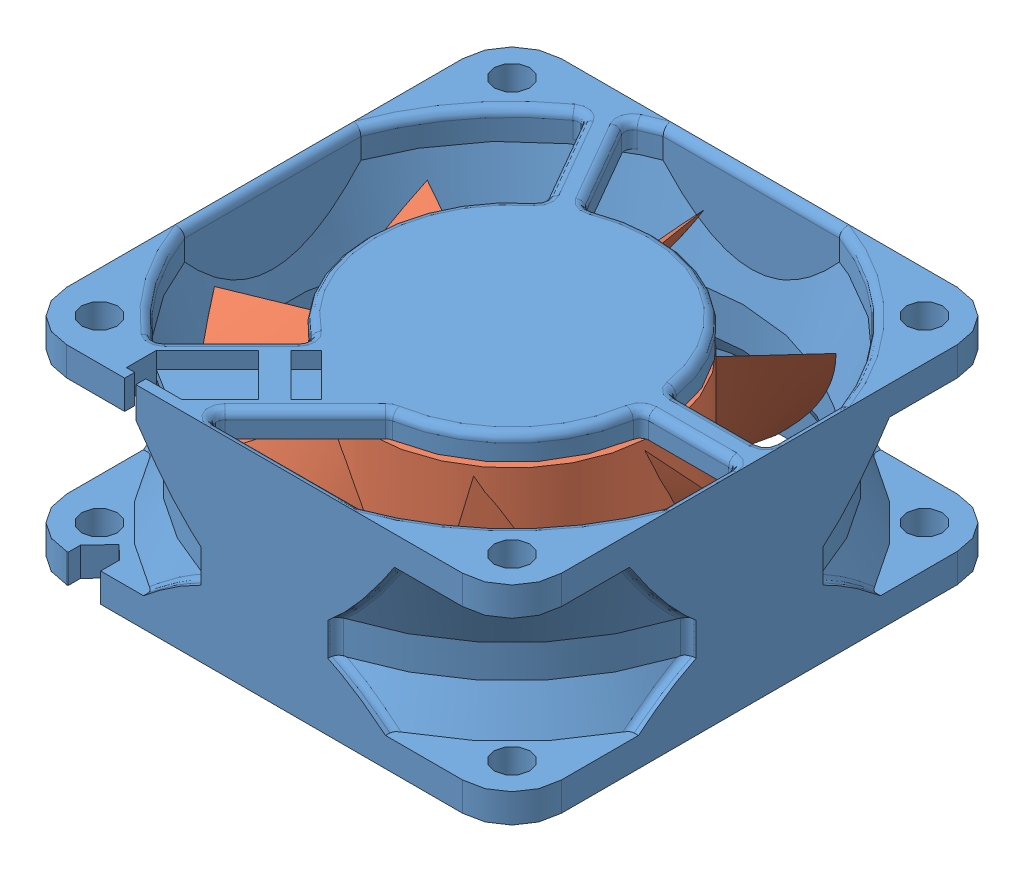
SolidWorks assembly Ventola_50x50, configuration Default. Lengths in mm.
Overall size (60.11 25.2 60.11).
2 component instances, 2 part files, 6 mates.
Components (placement in the parent):
- ventola_1-1: ventola_1 [Default] at origin size (60.11 25.2 60.11)
- ventola_2-1: ventola_2 [Default] at origin size (57.21 21.2 55.9)
Mates (geometry in assembly coordinates):
- Coincidente1: coincident aligned: plane of ventola_1-1 through (0 0 0) normal (0 0 1); plane of assembly through (0 0 0) normal (0 0 1)
- Coincidente2: coincident aligned: plane of ventola_1-1 through (0 0 0) normal (0 1 0); plane of assembly through (0 0 0) normal (0 1 0)
- Coincidente3: coincident aligned: plane of ventola_1-1 through (0 0 0) normal (1 0 0); plane of assembly through (0 0 0) normal (1 0 0)
- Coincidente4: coincident aligned: plane of ventola_2-1 through (0 0 0) normal (0 0 1); plane of assembly through (0 0 0) normal (0 0 1)
- Coincidente5: coincident aligned: plane of ventola_2-1 through (0 0 0) normal (0 1 0); plane of assembly through (0 0 0) normal (0 1 0)
- Coincidente6: coincident aligned: plane of ventola_2-1 through (0 0 0) normal (1 0 0); plane of assembly through (0 0 0) normal (1 0 0)
